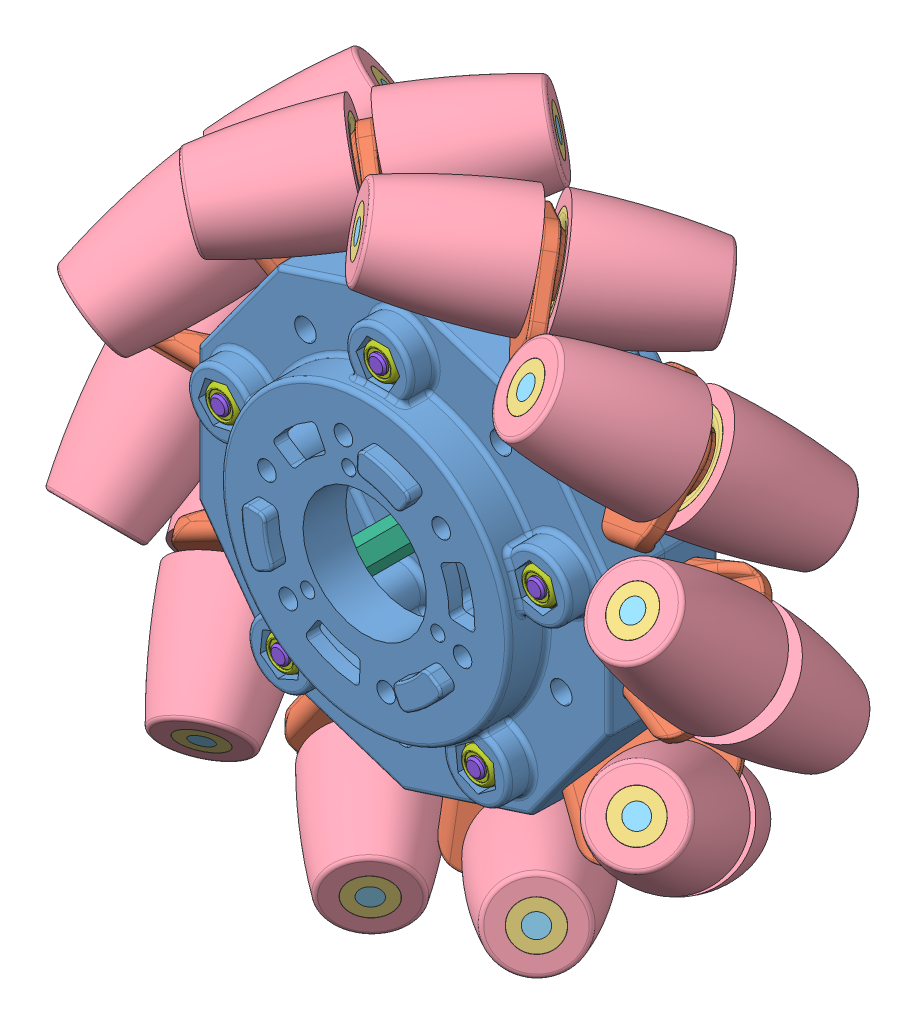
SolidWorks assembly LEFT, configuration Default. Lengths in mm.
Overall size (160.5 167.62 65.82).
98 component instances, 9 part files, 0 mates.
Components (placement in the parent):
- 217-2799-001 Rev1-1: 217-2799-001 Rev1 [Default] at (0 0 6.35) size (95.78 100.46 28.55)
- 217-2799-001 Rev1-2: 217-2799-001 Rev1 [Default] at (0 0 -6.35) x (-0.809017 0.587785 0) z (0 0 -1) size (95.78 100.46 28.55)
- 217-2799-002 Rev1-1: 217-2799-002 Rev1 [Default] at (-41.4796 0 0) x (0 1 0) z (-1 0 0) size (26.84 25.28 30.09)
- 217-2586-003 Rev2-1: 217-2586-003 Rev2 [Default] at (-62.2568 4.0062 -4.0062) x (0.900568 0.30739 0.30739) z (-0.434715 0.636798 0.636798) size (19.46 28.57 19.46)
- 217-2586-003 Rev2-2: 217-2586-003 Rev2 [Default] at (-62.2568 -4.0062 4.0062) x (0.918161 -0.280161 -0.280161) z (-0.396207 -0.649238 -0.649238) size (19.46 28.57 19.46)
- 217-2586-004 Rev1-1: 217-2586-004 Rev1 [Default] at (-62.2568 -0.4056 0.4056) x (-0.999474 -0.02293 -0.02293) z (0.032428 -0.706735 -0.706735) size (25.9 28.58 25.9)
- 217-2586-004 Rev1-2: 217-2586-004 Rev1 [Default] at (-62.2568 0.4047 -0.4047) x (-0.563522 -0.584142 -0.584142) z (-0.826101 0.39847 0.39847) size (25.9 28.58 25.9)
- 217-2586-007 Rev1-1: 217-2586-007 Rev1 [Default] at (-62.2568 0 0) x (0 -0.707107 0.707107) z (-0.999992 0.002763 0.002763) size (61.72 5 5)
- 217-2586-008 Rev1-1: 217-2586-008 Rev1 [Default] at (4.9509 -23.2921 -0.127) x (0.978148 0.207912 0) z (0 0 -1) size (7.33 6.35 31.75)
- NUT-832-NYLOCK-1: NUT-832-NYLOCK [Default] at (0 38.5 13.6563) x (-0.5 -0.866025 0) z (-0.866025 0.5 0) size (10.2 5.86 8.12)
- SCREW-832-1250-1: SCREW-832-1250 [Default] at (0 38.5 -14.9098) x (0 0 1) z (0.371063 0.928608 0) size (33.96 7.92 7.92)
- 217-2586-007 Rev1-2: 217-2586-007 Rev1 [Default] at (-50.3668 36.5937 0) x (-0.415627 -0.572061 0.707107) z (-0.807387 0.590016 0.002763) size (61.72 5 5)
- 217-2586-007 Rev1-3: 217-2586-007 Rev1 [Default] at (-19.2384 59.2098 0) x (-0.672499 -0.218508 0.707107) z (-0.306387 0.951903 0.002763) size (61.72 5 5)
- 217-2586-007 Rev1-4: 217-2586-007 Rev1 [Default] at (19.2384 59.2098 0) x (-0.672499 0.218508 0.707107) z (0.311642 0.950196 0.002763) size (61.72 5 5)
- 217-2586-007 Rev1-5: 217-2586-007 Rev1 [Default] at (50.3668 36.5937 0) x (-0.415627 0.572061 0.707107) z (0.810635 0.585546 0.002763) size (61.72 5 5)
- 217-2586-007 Rev1-6: 217-2586-007 Rev1 [Default] at (62.2568 0 0) x (0 0.707107 0.707107) z (0.999992 -0.002763 0.002763) size (61.72 5 5)
- 217-2586-007 Rev1-7: 217-2586-007 Rev1 [Default] at (50.3668 -36.5937 0) x (0.415627 0.572061 0.707107) z (0.807387 -0.590016 0.002763) size (61.72 5 5)
- 217-2586-007 Rev1-8: 217-2586-007 Rev1 [Default] at (19.2384 -59.2098 0) x (0.672499 0.218508 0.707107) z (0.306387 -0.951903 0.002763) size (61.72 5 5)
- 217-2586-007 Rev1-9: 217-2586-007 Rev1 [Default] at (-19.2384 -59.2098 0) x (0.672499 -0.218508 0.707107) z (-0.311642 -0.950196 0.002763) size (61.72 5 5)
- 217-2586-007 Rev1-10: 217-2586-007 Rev1 [Default] at (-50.3668 -36.5937 0) x (0.415627 -0.572061 0.707107) z (-0.810635 -0.585546 0.002763) size (61.72 5 5)
- 217-2586-004 Rev1-3: 217-2586-004 Rev1 [Default] at (-50.129 36.921 -0.4047) x (-0.799249 -0.14135 -0.584142) z (-0.434115 0.807939 0.39847) size (25.9 28.58 25.9)
- 217-2586-004 Rev1-4: 217-2586-004 Rev1 [Default] at (-18.8536 59.3348 -0.4047) x (-0.72969 0.355432 -0.584142) z (0.123689 0.908803 0.39847) size (25.9 28.58 25.9)
- 217-2586-004 Rev1-5: 217-2586-004 Rev1 [Default] at (19.6233 59.0847 -0.4047) x (-0.381414 0.716451 -0.584142) z (0.634247 0.662535 0.39847) size (25.9 28.58 25.9)
- 217-2586-004 Rev1-6: 217-2586-004 Rev1 [Default] at (50.6047 36.2663 -0.4047) x (0.112549 0.80381 -0.584142) z (0.902545 0.163201 0.39847) size (25.9 28.58 25.9)
- 217-2586-004 Rev1-7: 217-2586-004 Rev1 [Default] at (62.2568 -0.4047 -0.4047) x (0.563522 0.584142 -0.584142) z (0.826101 -0.39847 0.39847) size (25.9 28.58 25.9)
- 217-2586-004 Rev1-8: 217-2586-004 Rev1 [Default] at (50.129 -36.921 -0.4047) x (0.799249 0.14135 -0.584142) z (0.434115 -0.807939 0.39847) size (25.9 28.58 25.9)
- 217-2586-004 Rev1-9: 217-2586-004 Rev1 [Default] at (18.8536 -59.3348 -0.4047) x (0.72969 -0.355432 -0.584142) z (-0.123689 -0.908803 0.39847) size (25.9 28.58 25.9)
- 217-2586-004 Rev1-10: 217-2586-004 Rev1 [Default] at (-19.6233 -59.0847 -0.4047) x (0.381414 -0.716451 -0.584142) z (-0.634247 -0.662535 0.39847) size (25.9 28.58 25.9)
- 217-2586-004 Rev1-11: 217-2586-004 Rev1 [Default] at (-50.6047 -36.2663 -0.4047) x (-0.112549 -0.80381 -0.584142) z (-0.902545 -0.163201 0.39847) size (25.9 28.58 25.9)
- 217-2586-004 Rev1-12: 217-2586-004 Rev1 [Default] at (-50.6053 36.2655 0.4056) x (-0.82207 0.568925 -0.02293) z (-0.389173 -0.590821 -0.706735) size (25.9 28.58 25.9)
- 217-2586-004 Rev1-13: 217-2586-004 Rev1 [Default] at (-19.6242 59.0844 0.4056) x (-0.330662 0.943471 -0.02293) z (-0.662124 -0.249234 -0.706735) size (25.9 28.58 25.9)
- 217-2586-004 Rev1-14: 217-2586-004 Rev1 [Default] at (18.8527 59.3351 0.4056) x (0.287047 0.957642 -0.02293) z (-0.682166 0.187552 -0.706735) size (25.9 28.58 25.9)
- 217-2586-004 Rev1-15: 217-2586-004 Rev1 [Default] at (50.1284 36.9218 0.4056) x (0.795114 0.606027 -0.02293) z (-0.441643 0.5527 -0.706735) size (25.9 28.58 25.9)
- 217-2586-004 Rev1-16: 217-2586-004 Rev1 [Default] at (62.2568 0.4056 0.4056) x (0.999474 0.02293 -0.02293) z (-0.032428 0.706735 -0.706735) size (25.9 28.58 25.9)
- 217-2586-004 Rev1-17: 217-2586-004 Rev1 [Default] at (50.6053 -36.2655 0.4056) x (0.82207 -0.568925 -0.02293) z (0.389173 0.590821 -0.706735) size (25.9 28.58 25.9)
- 217-2586-004 Rev1-18: 217-2586-004 Rev1 [Default] at (19.6242 -59.0844 0.4056) x (0.330662 -0.943471 -0.02293) z (0.662124 0.249234 -0.706735) size (25.9 28.58 25.9)
- 217-2586-004 Rev1-19: 217-2586-004 Rev1 [Default] at (-18.8527 -59.3351 0.4056) x (-0.287047 -0.957642 -0.02293) z (0.682166 -0.187552 -0.706735) size (25.9 28.58 25.9)
- 217-2586-004 Rev1-20: 217-2586-004 Rev1 [Default] at (-50.1284 -36.9218 0.4056) x (-0.795114 -0.606027 -0.02293) z (0.441643 -0.5527 -0.706735) size (25.9 28.58 25.9)
- 217-2586-003 Rev2-3: 217-2586-003 Rev2 [Default] at (-52.7216 33.3525 4.0062) x (0.578133 -0.766336 -0.280161) z (-0.702151 -0.29236 -0.649238) size (19.46 28.57 19.46)
- 217-2586-003 Rev2-4: 217-2586-003 Rev2 [Default] at (-23.0486 57.9718 4.0062) x (0.017279 -0.959798 -0.280161) z (-0.739897 0.17619 -0.649238) size (19.46 28.57 19.46)
- 217-2586-003 Rev2-5: 217-2586-003 Rev2 [Default] at (15.4283 60.4478 4.0062) x (-0.550176 -0.786649 -0.280161) z (-0.495027 0.577441 -0.649238) size (19.46 28.57 19.46)
- 217-2586-003 Rev2-6: 217-2586-003 Rev2 [Default] at (48.012 39.8348 4.0062) x (-0.907482 -0.313027 -0.280161) z (-0.061074 0.758129 -0.649238) size (19.46 28.57 19.46)
- 217-2586-003 Rev2-7: 217-2586-003 Rev2 [Default] at (62.2568 4.0062 4.0062) x (-0.918161 0.280161 -0.280161) z (0.396207 0.649238 -0.649238) size (19.46 28.57 19.46)
- 217-2586-003 Rev2-8: 217-2586-003 Rev2 [Default] at (52.7216 -33.3525 4.0062) x (-0.578133 0.766336 -0.280161) z (0.702151 0.29236 -0.649238) size (19.46 28.57 19.46)
- 217-2586-003 Rev2-9: 217-2586-003 Rev2 [Default] at (23.0486 -57.9718 4.0062) x (-0.017279 0.959798 -0.280161) z (0.739897 -0.17619 -0.649238) size (19.46 28.57 19.46)
- 217-2586-003 Rev2-10: 217-2586-003 Rev2 [Default] at (-15.4283 -60.4478 4.0062) x (0.550176 0.786649 -0.280161) z (0.495027 -0.577441 -0.649238) size (19.46 28.57 19.46)
- 217-2586-003 Rev2-11: 217-2586-003 Rev2 [Default] at (-48.012 -39.8348 4.0062) x (0.907482 0.313027 -0.280161) z (0.061074 -0.758129 -0.649238) size (19.46 28.57 19.46)
- 217-2586-003 Rev2-12: 217-2586-003 Rev2 [Default] at (-48.012 39.8348 -4.0062) x (0.909254 -0.280657 0.30739) z (0.022609 0.770699 0.636798) size (19.46 28.57 19.46)
- 217-2586-003 Rev2-13: 217-2586-003 Rev2 [Default] at (-15.4283 60.4478 -4.0062) x (0.570636 -0.761502 0.30739) z (0.471296 0.61022 0.636798) size (19.46 28.57 19.46)
- 217-2586-003 Rev2-14: 217-2586-003 Rev2 [Default] at (23.0486 57.9718 -4.0062) x (0.014054 -0.95148 0.30739) z (0.739965 0.216657 0.636798) size (19.46 28.57 19.46)
- 217-2586-003 Rev2-15: 217-2586-003 Rev2 [Default] at (52.7216 33.3525 -4.0062) x (-0.547896 -0.778024 0.30739) z (0.725992 -0.259661 0.636798) size (19.46 28.57 19.46)
- 217-2586-003 Rev2-16: 217-2586-003 Rev2 [Default] at (62.2568 -4.0062 -4.0062) x (-0.900568 -0.30739 0.30739) z (0.434715 -0.636798 0.636798) size (19.46 28.57 19.46)
- 217-2586-003 Rev2-17: 217-2586-003 Rev2 [Default] at (48.012 -39.8348 -4.0062) x (-0.909254 0.280657 0.30739) z (-0.022609 -0.770699 0.636798) size (19.46 28.57 19.46)
- 217-2586-003 Rev2-18: 217-2586-003 Rev2 [Default] at (15.4283 -60.4478 -4.0062) x (-0.570636 0.761502 0.30739) z (-0.471296 -0.61022 0.636798) size (19.46 28.57 19.46)
- 217-2586-003 Rev2-19: 217-2586-003 Rev2 [Default] at (-23.0486 -57.9718 -4.0062) x (-0.014054 0.95148 0.30739) z (-0.739965 -0.216657 0.636798) size (19.46 28.57 19.46)
- 217-2586-003 Rev2-20: 217-2586-003 Rev2 [Default] at (-52.7216 -33.3525 -4.0062) x (0.547896 0.778024 0.30739) z (-0.725992 0.259661 0.636798) size (19.46 28.57 19.46)
- 217-2799-002 Rev1-2: 217-2799-002 Rev1 [Default] at (-33.5577 24.3811 0) x (0.587785 0.809017 0) z (-0.809017 0.587785 0) size (26.84 25.28 30.09)
- 217-2799-002 Rev1-3: 217-2799-002 Rev1 [Default] at (-12.8179 39.4495 0) x (0.951057 0.309017 0) z (-0.309017 0.951057 0) size (26.84 25.28 30.09)
- 217-2799-002 Rev1-4: 217-2799-002 Rev1 [Default] at (12.8179 39.4495 0) x (0.951057 -0.309017 0) z (0.309017 0.951057 0) size (26.84 25.28 30.09)
- 217-2799-002 Rev1-5: 217-2799-002 Rev1 [Default] at (33.5577 24.3811 0) x (0.587785 -0.809017 0) z (0.809017 0.587785 0) size (26.84 25.28 30.09)
- 217-2799-002 Rev1-6: 217-2799-002 Rev1 [Default] at (41.4796 0 0) x (0 -1 0) z (1 0 0) size (26.84 25.28 30.09)
- 217-2799-002 Rev1-7: 217-2799-002 Rev1 [Default] at (33.5577 -24.3811 0) x (-0.587785 -0.809017 0) z (0.809017 -0.587785 0) size (26.84 25.28 30.09)
- 217-2799-002 Rev1-8: 217-2799-002 Rev1 [Default] at (12.8179 -39.4495 0) x (-0.951057 -0.309017 0) z (0.309017 -0.951057 0) size (26.84 25.28 30.09)
- 217-2799-002 Rev1-9: 217-2799-002 Rev1 [Default] at (-12.8179 -39.4495 0) x (-0.951057 0.309017 0) z (-0.309017 -0.951057 0) size (26.84 25.28 30.09)
- 217-2799-002 Rev1-10: 217-2799-002 Rev1 [Default] at (-33.5577 -24.3811 0) x (-0.587785 0.809017 0) z (-0.809017 -0.587785 0) size (26.84 25.28 30.09)
- 217-2586-008 Rev1-2: 217-2586-008 Rev1 [Default] at (-17.6961 -15.9337 -0.127) x (0.669131 -0.743145 0) z (0 0 -1) size (7.33 6.35 31.75)
- 217-2586-008 Rev1-3: 217-2586-008 Rev1 [Default] at (-22.647 7.3585 -0.127) x (-0.309017 -0.951057 0) z (0 0 -1) size (7.33 6.35 31.75)
- 217-2586-008 Rev1-4: 217-2586-008 Rev1 [Default] at (-4.9509 23.2921 -0.127) x (-0.978148 -0.207912 0) z (0 0 -1) size (7.33 6.35 31.75)
- 217-2586-008 Rev1-5: 217-2586-008 Rev1 [Default] at (17.6961 15.9337 -0.127) x (-0.669131 0.743145 0) z (0 0 -1) size (7.33 6.35 31.75)
- 217-2586-008 Rev1-6: 217-2586-008 Rev1 [Default] at (22.647 -7.3585 -0.127) x (0.309017 0.951057 0) z (0 0 -1) size (7.33 6.35 31.75)
- SCREW-832-1250-2: SCREW-832-1250 [Default] at (-36.6157 11.8972 -14.9098) x (0 0 1) z (-0.768494 0.639858 0) size (33.96 7.92 7.92)
- SCREW-832-1250-3: SCREW-832-1250 [Default] at (-22.6297 -31.1472 -14.9098) x (0 0 1) z (-0.846018 -0.533154 0) size (33.96 7.92 7.92)
- SCREW-832-1250-4: SCREW-832-1250 [Default] at (22.6297 -31.1472 -14.9098) x (0 0 1) z (0.245625 -0.969365 0) size (33.96 7.92 7.92)
- SCREW-832-1250-5: SCREW-832-1250 [Default] at (36.6157 11.8972 -14.9098) x (0 0 1) z (0.997823 -0.065947 0) size (33.96 7.92 7.92)
- NUT-832-NYLOCK-2: NUT-832-NYLOCK [Default] at (-36.6157 11.8972 13.6563) x (0.669131 -0.743145 0) z (-0.743145 -0.669131 0) size (10.2 5.86 8.12)
- NUT-832-NYLOCK-3: NUT-832-NYLOCK [Default] at (-22.6297 -31.1472 13.6563) x (0.913545 0.406737 0) z (0.406737 -0.913545 0) size (10.2 5.86 8.12)
- NUT-832-NYLOCK-4: NUT-832-NYLOCK [Default] at (22.6297 -31.1472 13.6563) x (-0.104528 0.994522 0) z (0.994522 0.104528 0) size (10.2 5.86 8.12)
- NUT-832-NYLOCK-5: NUT-832-NYLOCK [Default] at (36.6157 11.8972 13.6563) x (-0.978148 0.207912 0) z (0.207912 0.978148 0) size (10.2 5.86 8.12)
- 217-2586-005 Rev2-1: 217-2586-005 Rev2 [Default] at (-62.2568 -6.3286 6.3286) x (0 0.707107 -0.707107) z (0.707107 0.5 0.5) size (8.5 8 8)
- 217-2586-005 Rev2-2: 217-2586-005 Rev2 [Default] at (-62.2568 6.3286 -6.3286) x (0 0.707107 -0.707107) z (0.707107 0.5 0.5) size (8.5 8 8)
- 217-2586-005 Rev2-3: 217-2586-005 Rev2 [Default] at (-46.647 41.7136 -6.3286) x (0.415627 0.572061 -0.707107) z (0.865954 -0.011118 0.5) size (8.5 8 8)
- 217-2586-005 Rev2-4: 217-2586-005 Rev2 [Default] at (-13.2196 61.1654 -6.3286) x (0.672499 0.218508 -0.707107) z (0.694036 -0.51799 0.5) size (8.5 8 8)
- 217-2586-005 Rev2-5: 217-2586-005 Rev2 [Default] at (25.2573 57.2541 -6.3286) x (0.672499 -0.218508 -0.707107) z (0.25702 -0.827007 0.5) size (8.5 8 8)
- 217-2586-005 Rev2-6: 217-2586-005 Rev2 [Default] at (54.0867 31.4737 -6.3286) x (0.415627 -0.572061 -0.707107) z (-0.278169 -0.820135 0.5) size (8.5 8 8)
- 217-2586-005 Rev2-7: 217-2586-005 Rev2 [Default] at (62.2568 -6.3286 -6.3286) x (0 -0.707107 -0.707107) z (-0.707107 -0.5 0.5) size (8.5 8 8)
- 217-2586-005 Rev2-8: 217-2586-005 Rev2 [Default] at (46.647 -41.7136 -6.3286) x (-0.415627 -0.572061 -0.707107) z (-0.865954 0.011118 0.5) size (8.5 8 8)
- 217-2586-005 Rev2-9: 217-2586-005 Rev2 [Default] at (13.2196 -61.1654 -6.3286) x (-0.672499 -0.218508 -0.707107) z (-0.694036 0.51799 0.5) size (8.5 8 8)
- 217-2586-005 Rev2-10: 217-2586-005 Rev2 [Default] at (-25.2573 -57.2541 -6.3286) x (-0.672499 0.218508 -0.707107) z (-0.25702 0.827007 0.5) size (8.5 8 8)
- 217-2586-005 Rev2-11: 217-2586-005 Rev2 [Default] at (-54.0867 -31.4737 -6.3286) x (-0.415627 0.572061 -0.707107) z (0.278169 0.820135 0.5) size (8.5 8 8)
- 217-2586-005 Rev2-12: 217-2586-005 Rev2 [Default] at (-54.0867 31.4737 6.3286) x (0.415627 0.572061 -0.707107) z (0.865954 -0.011118 0.5) size (8.5 8 8)
- 217-2586-005 Rev2-13: 217-2586-005 Rev2 [Default] at (-25.2573 57.2541 6.3286) x (0.672499 0.218508 -0.707107) z (0.694036 -0.51799 0.5) size (8.5 8 8)
- 217-2586-005 Rev2-14: 217-2586-005 Rev2 [Default] at (13.2196 61.1654 6.3286) x (0.672499 -0.218508 -0.707107) z (0.25702 -0.827007 0.5) size (8.5 8 8)
- 217-2586-005 Rev2-15: 217-2586-005 Rev2 [Default] at (46.647 41.7136 6.3286) x (0.415627 -0.572061 -0.707107) z (-0.278169 -0.820135 0.5) size (8.5 8 8)
- 217-2586-005 Rev2-16: 217-2586-005 Rev2 [Default] at (62.2568 6.3286 6.3286) x (0 -0.707107 -0.707107) z (-0.707107 -0.5 0.5) size (8.5 8 8)
- 217-2586-005 Rev2-17: 217-2586-005 Rev2 [Default] at (54.0867 -31.4737 6.3286) x (-0.415627 -0.572061 -0.707107) z (-0.865954 0.011118 0.5) size (8.5 8 8)
- 217-2586-005 Rev2-18: 217-2586-005 Rev2 [Default] at (25.2573 -57.2541 6.3286) x (-0.672499 -0.218508 -0.707107) z (-0.694036 0.51799 0.5) size (8.5 8 8)
- 217-2586-005 Rev2-19: 217-2586-005 Rev2 [Default] at (-13.2196 -61.1654 6.3286) x (-0.672499 0.218508 -0.707107) z (-0.25702 0.827007 0.5) size (8.5 8 8)
- 217-2586-005 Rev2-20: 217-2586-005 Rev2 [Default] at (-46.647 -41.7136 6.3286) x (-0.415627 0.572061 -0.707107) z (0.278169 0.820135 0.5) size (8.5 8 8)
